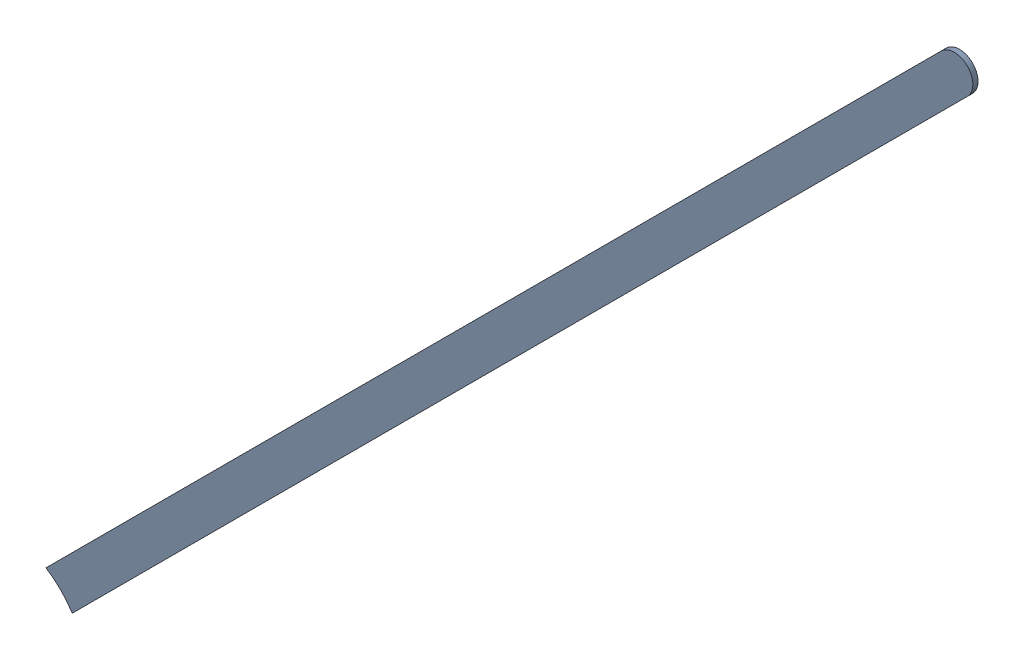
SolidWorks assembly Track (13.758mm,4.578mm)(20.3mm,11.119mm) on Bottom Layer, configuration Predeterminado. Lengths in mm.
Overall size (6.35 6.35 0.04).
2 component instances, 1 part files, 0 mates.
Components (placement in the parent):
- Track (13.758mm,4.578mm)(20.3mm,11.119mm) on Bottom Layer-1-1: Track (13.758mm,4.578mm)(20.3mm,11.119mm) on Bottom Layer-1 [Predeterminado] at (-68.317 -44.187 -0.4013) size (6.35 6.35 0.04)
  - Track (13.758mm,4.578mm)(20.3mm,11.119mm) on Bottom Layer-Part-1-1: Track (13.758mm,4.578mm)(20.3mm,11.119mm) on Bottom Layer-Part-1 [Predeterminado] at origin size (6.35 6.35 0.04)
